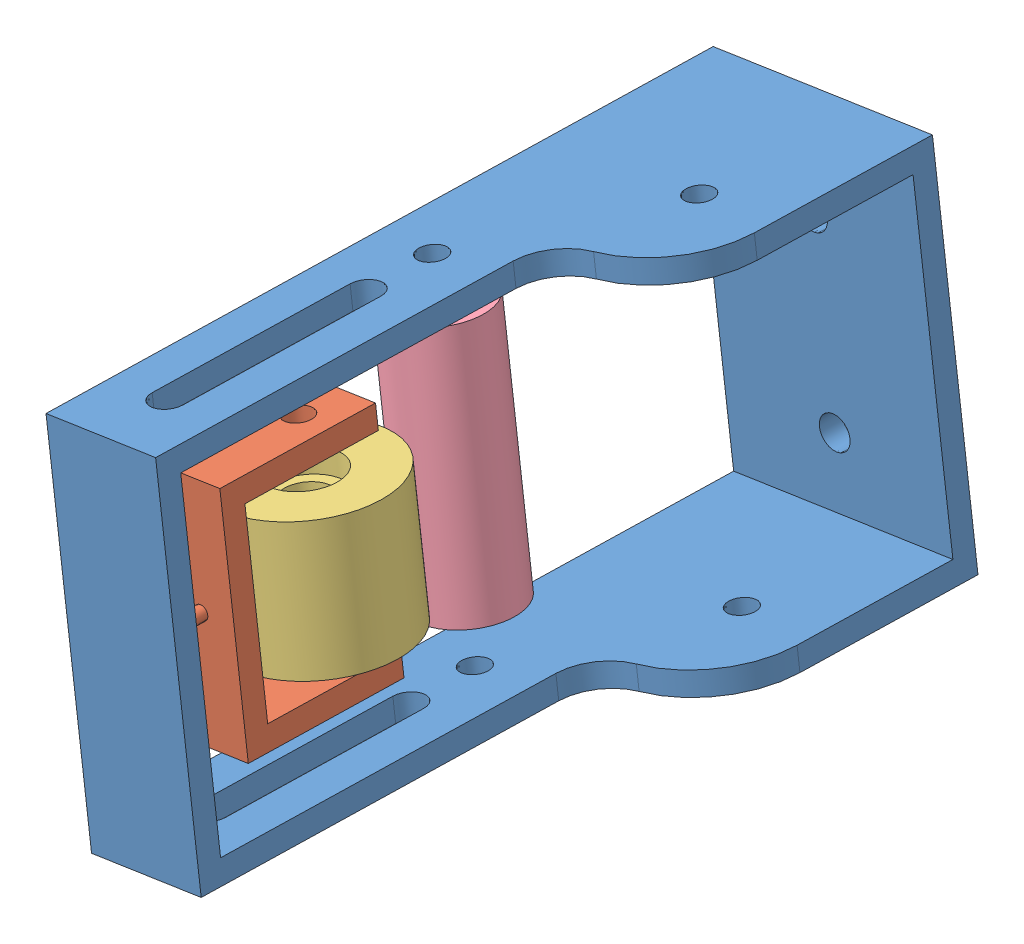
SolidWorks assembly Assem1, configuration Default. Lengths in mm.
Overall size (67.4 89.65 151.64).
4 component instances, 4 part files, 6 mates.
Components (placement in the parent):
- housing-2: housing [Default] at (13.0808 62.0721 95.7709) x (-0.149301 0.988571 -0.020883) z (0.988787 0.149334 0) size (80 150 50)
- upper_roller_holder-1: upper_roller_holder [Default] at (0.6038 60.9809 133.3175) x (0.149301 -0.988571 0.020883) z (-0.988787 -0.149334 0) size (50 39 15)
- upper_roller-1: upper_roller [Default] at (0.6265 60.8307 128.3196) x (0.941236 0.135618 -0.309327) z (0.30296 0.065839 0.950726) size (35 29 35)
- lower roler-1: lower roler [Default] at (0.0164 64.8706 96.1725) x (0.149301 -0.988571 0.020883) z (0.893072 0.125753 -0.431982) size (55 21 21)
Mates (geometry in assembly coordinates):
- Parallel1: parallel aligned: plane of housing-2 through (19.0696 22.4181 91.2231) normal (0.988787 0.149334 0); plane of upper_roller_holder-1 through (8.0197 62.1009 133.3175) normal (0.988787 0.149334 0)
- Parallel2: parallel aligned: plane of housing-2 through (42.7921 32.7541 171.4854) normal (-0.003119 0.020649 0.999782); plane of upper_roller_holder-1 through (-9.8605 80.0453 152.8955) normal (-0.003119 0.020649 0.999782)
- Concentric3: concentric anti-aligned: cylinder of housing-2 through (0.5151 61.5682 161.7565) axis (-0.003119 0.020649 0.999782) radius 1.5; cylinder of upper_roller_holder-1 through (0.529 61.4765 157.3123) axis (0.003119 -0.020649 -0.999782) radius 1.5
- Concentric4: concentric anti-aligned: cylinder of upper_roller_holder-1 through (-3.1131 85.5919 127.7965) axis (0.149301 -0.988571 0.020883) radius 3; cylinder of upper_roller-1 through (-1.7694 76.6948 127.9845) axis (-0.149301 0.988571 -0.020883) radius 7.5
- Distance1: distance = 5 mm anti-aligned: plane of upper_roller-1 through (14.8515 78.0795 122.5921) normal (-0.149301 0.988571 -0.020883); plane of upper_roller_holder-1 through (-9.8449 79.942 147.8966) normal (0.149301 -0.988571 0.020883)
- Concentric5: concentric aligned: cylinder of housing-2 through (6.6914 20.6729 97.1061) axis (-0.149301 0.988571 -0.020883) radius 3; cylinder of lower roler-1 through (-4.0894 92.0563 95.5982) axis (-0.149301 0.988571 -0.020883) radius 5
